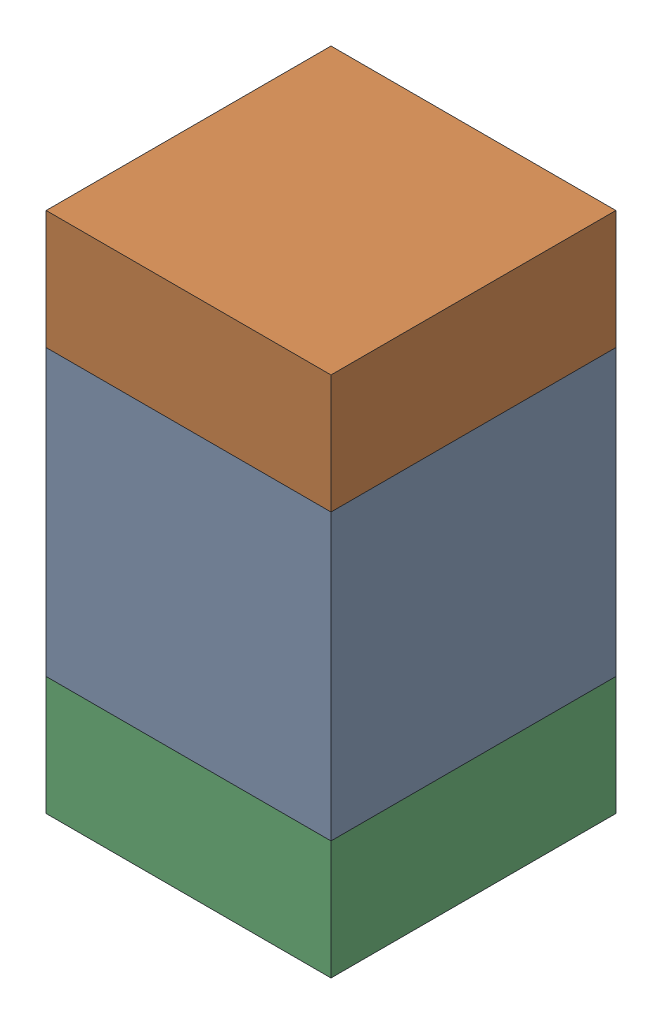
SolidWorks assembly C113_1PCB, configuration Default. Lengths in mm.
Overall size (0.6 1.1 0.6).
6 component instances, 2 part files, 0 mates.
Components (placement in the parent):
- 761606048-1: 761606048 [Default] at (116.1 118.9 0) size (0.6 0.6 0.6)
  - Extruded_9-1: Extruded_9 [Default] at origin size (0.6 0.6 0.6)
- 854785296-1: 854785296 [Default] at (116.1 119.325 0) size (0.6 0.25 0.6)
  - Extruded_10-1: Extruded_10 [Default] at origin size (0.6 0.25 0.6)
- 854785296-2: 854785296 [Default] at (116.1 118.475 0) size (0.6 0.25 0.6)
  - Extruded_10-1: Extruded_10 [Default] at origin size (0.6 0.25 0.6)
